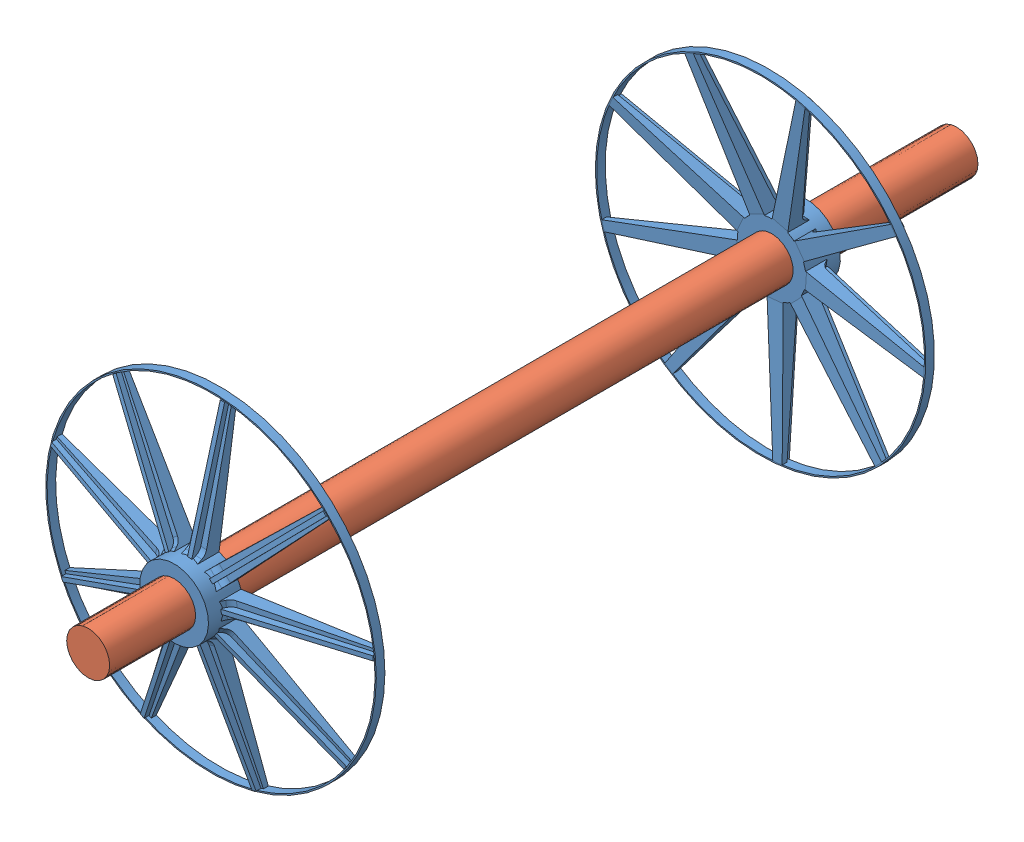
SolidWorks assembly Assem2, configuration Default. Lengths in mm.
Overall size (543.73 543.73 1010).
3 component instances, 2 part files, 5 mates.
Components (placement in the parent):
- cylinder_support-1: cylinder_support [Default] at (0 0 175) x (-0.828223 0.560399 0) z (0 0 1) size (384.5 384.5 52.9)
- cylinder_shaft-2: cylinder_shaft [Default] at origin size (50 50 1010)
- cylinder_support-2: cylinder_support [Default] at (0 0 910) x (-0.714709 0.699422 0) z (0 0 -1) size (384.5 384.5 52.9)
Mates (geometry in assembly coordinates):
- Coincident3: coordinate: point of cylinder_shaft-2; point of assembly
- Concentric1: concentric: circle of cylinder_support-1; circle of cylinder_shaft-2
- Distance2: distance = 175 mm: plane of cylinder_support-1 through (0 0 175) normal (0 0 -1); plane of cylinder_shaft-2 through (0 0 0) normal (0 0 -1)
- Distance3: distance = 100 mm: plane of cylinder_support-2 through (0 0 910) normal (0 0 1); plane of cylinder_shaft-2 through (0 0 1010) normal (0 0 1)
- Concentric2: concentric: circle of cylinder_shaft-2; circle of cylinder_support-2
